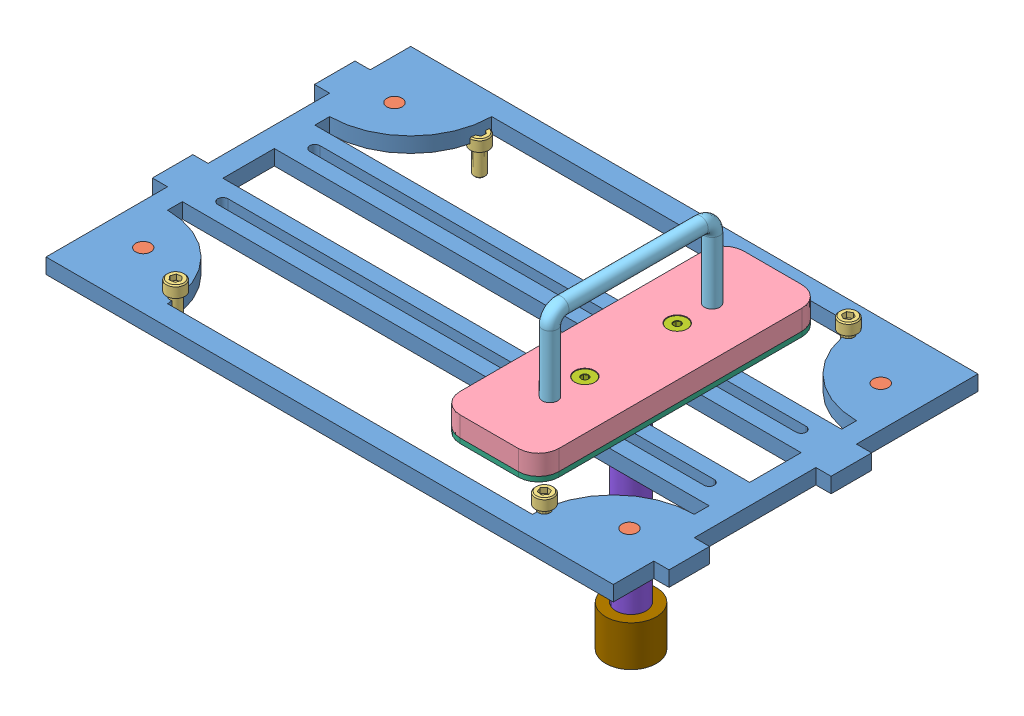
SolidWorks assembly Killswitch4, configuration Default. Lengths in mm.
Overall size (187.33 106.62 114.3).
21 component instances, 10 part files, 30 mates.
Components (placement in the parent):
- Panel-2: Panel [Default] at origin size (187.33 4.76 114.3)
- Magnet-1: Magnet [Default] at (76.2 2.3813 39.37) size (4.76 4.76 4.76)
- Magnet-2: Magnet [Default] at (76.2 2.3813 -39.37) size (4.76 4.76 4.76)
- Magnet-3: Magnet [Default] at (-76.2 2.3813 -39.37) size (4.76 4.76 4.76)
- Magnet-4: Magnet [Default] at (-76.2 2.3813 39.37) size (4.76 4.76 4.76)
- socket head cap screw_ai-2: socket head cap screw_ai [HX-SHCS 0.138-40x0.3125x0.3125-C] at (-57.785 1.819 -47.625) x (0 -1 0) z (0.436855 0 0.899532) size (11.44 5.74 5.74)
- socket head cap screw_ai-3: socket head cap screw_ai [HX-SHCS 0.138-40x0.3125x0.3125-C] at (57.785 9.7917 -47.625) x (0 -1 0) z (-0.495278 0 0.868734) size (11.44 5.74 5.74)
- socket head cap screw_ai-4: socket head cap screw_ai [HX-SHCS 0.138-40x0.3125x0.3125-C] at (57.785 9.7917 47.625) x (0 -1 0) z (-0.933448 0 0.358714) size (11.44 5.74 5.74)
- socket head cap screw_ai-5: socket head cap screw_ai [HX-SHCS 0.138-40x0.3125x0.3125-C] at (-57.785 9.7917 47.625) x (0 -1 0) z (0.168939 0 0.985627) size (11.44 5.74 5.74)
- Slider-2: Slider [Default] at (37.3018 12.573 -0.003) x (-1 0 0) z (0 0 1) size (30.96 6.29 88.9)
- Magnet-7: Magnet [Default] at (37.3018 10.1917 -39.119) size (4.76 4.76 4.76)
- Magnet-8: Magnet [Default] at (37.3018 10.1917 39.113) size (4.76 4.76 4.76)
- 1568A630-1: 1568A630 [1568A63] at (37.3018 37.1158 -0.003) x (0 0 1) z (1 0 0) size (55.56 25.63 4.76)
- SliderAcrylic-1: SliderAcrylic [Default] at (37.3018 6.2865 -0.003) size (30.96 1.52 88.9)
- socket head cap screw_ai-6: socket head cap screw_ai [HX-SHCS 0.112-40x0.4375x0.4375-C] at (37.3018 3.4417 -25.403) x (0 1 0) z (0 0 1) size (13.96 4.65 4.65)
- socket head cap screw_ai-7: socket head cap screw_ai [HX-SHCS 0.112-40x0.4375x0.4375-C] at (37.3018 3.4417 25.397) x (0 1 0) z (-0.253818 0 0.967252) size (13.96 4.65 4.65)
- 97345A428-3: 97345A428 [97345A428] at (37.3018 10.795 14.475) size (6.35 20.18 6.35)
- 97345A428-4: 97345A428 [97345A428] at (37.3018 10.795 -14.481) size (6.35 20.18 6.35)
- MagnetHolderB-1: MagnetHolderB [Default] at (37.3018 -27.4955 -0.003) x (0.135705 0 0.990749) z (-0.990749 0 0.135705) size (9.53 76.2 9.53)
- MagnetCapAcrylic-1: MagnetCapAcrylic [Default] at (37.3018 -67.1195 -0.003) x (0.50888 0 0.860837) z (-0.860837 0 0.50888) size (15.88 12.7 15.88)
- BigMagnet-1: BigMagnet [Default] at (37.3018 -65.5955 -0.003) size (6.35 6.35 6.35)
Mates (geometry in assembly coordinates):
- Coincident1: coincident aligned: circle of Panel-2; circle of Magnet-1
- Coincident2: coincident aligned: circle of Panel-2; circle of Magnet-2
- Coincident3: coincident aligned: circle of Panel-2; circle of Magnet-4
- Coincident4: coincident aligned: circle of Panel-2; circle of Magnet-3
- Concentric81: concentric: cylinder of Panel-2 through (-57.785 6.2865 -47.625) axis (0 1 0) radius 1.3526; cylinder of socket head cap screw_ai-2 through (-57.785 33.569 -47.625) axis (0 1 0) radius 2.8702
- Concentric91: concentric: cylinder of Panel-2 through (57.785 6.2865 -47.625) axis (0 1 0) radius 1.3526; cylinder of socket head cap screw_ai-3 through (57.785 41.5417 -47.625) axis (0 1 0) radius 2.8702
- Concentric101: concentric: cylinder of Panel-2 through (57.785 6.2865 47.625) axis (0 1 0) radius 1.3526; cylinder of socket head cap screw_ai-4 through (57.785 41.5417 47.625) axis (0 1 0) radius 2.8702
- Concentric111: concentric: cylinder of Panel-2 through (-57.785 6.2865 47.625) axis (0 1 0) radius 1.3526; cylinder of socket head cap screw_ai-5 through (-57.785 41.5417 47.625) axis (0 1 0) radius 2.8702
- Tangent1: tangent anti-aligned: plane of Panel-2 through (-76.2 0 -16.005) normal (0 0 1); cylinder of Slider-2 through (37.3018 7.8105 -14.481) axis (0 1 0) radius 1.524
- Parallel1: parallel aligned: plane of Panel-2 through (-164.5488 4.7625 57.15) normal (0 0 1); plane of Slider-2 through (52.7799 7.8105 44.447) normal (0 0 1)
- Coincident36: coincident aligned: circle of Slider-2; circle of Magnet-7
- Coincident37: coincident aligned: circle of Slider-2; circle of Magnet-8
- Concentric13: concentric aligned: circle of Slider-2; circle of 1568A630-1
- Concentric14: concentric anti-aligned: circle of Slider-2; circle of 1568A630-1
- Coincident38: coincident anti-aligned: plane of Slider-2 through (28.1737 14.097 -38.103) normal (0 1 0); plane of 1568A630-1 through (37.3018 14.097 25.397) normal (0 -1 0)
- Coincident39: coincident anti-aligned: plane of Slider-2 through (21.8237 7.8105 -44.453) normal (0 -1 0); plane of SliderAcrylic-1 through (52.7799 7.8105 -44.453) normal (0 1 0)
- Concentric15: concentric anti-aligned: circle of Slider-2; circle of SliderAcrylic-1
- Concentric16: concentric aligned: circle of Slider-2; circle of socket head cap screw_ai-7
- Coincident44: coincident anti-aligned: plane of SliderAcrylic-1 through (52.7799 6.2865 -44.453) normal (0 -1 0); plane of socket head cap screw_ai-7 through (35.0538 6.2865 24.8071) normal (0 1 0)
- Concentric17: concentric aligned: circle of Slider-2; circle of socket head cap screw_ai-6
- Coincident45: coincident anti-aligned: plane of SliderAcrylic-1 through (52.7799 6.2865 -44.453) normal (0 -1 0); plane of socket head cap screw_ai-6 through (34.9777 6.2865 -25.403) normal (0 1 0)
- Concentric22: concentric aligned: circle of Slider-2; circle of 97345A428-3
- Coincident70: coincident anti-aligned: plane of Slider-2 through (37.3018 10.795 14.475) normal (0 1 0); plane of 97345A428-3 through (37.3018 10.795 14.475) normal (0 -1 0)
- Concentric23: concentric aligned: circle of Slider-2; circle of 97345A428-4
- Coincident71: coincident anti-aligned: plane of Slider-2 through (37.3018 10.795 -14.481) normal (0 1 0); plane of 97345A428-4 through (37.3018 10.795 -14.481) normal (0 -1 0)
- Concentric112: concentric anti-aligned: circle of Slider-2; circle of MagnetHolderB-1
- Coincident72: coincident anti-aligned: circle of Slider-2; plane of MagnetHolderB-1 through (37.3018 10.6045 -0.003) normal (0 1 0)
- Concentric113: concentric aligned: circle of MagnetHolderB-1; circle of MagnetCapAcrylic-1
- Coincident76: coincident anti-aligned: plane of MagnetHolderB-1 through (37.3018 -65.5955 -0.003) normal (0 -1 0); circle of MagnetCapAcrylic-1
- Coincident78: coincident anti-aligned: circle of MagnetHolderB-1; circle of BigMagnet-1
